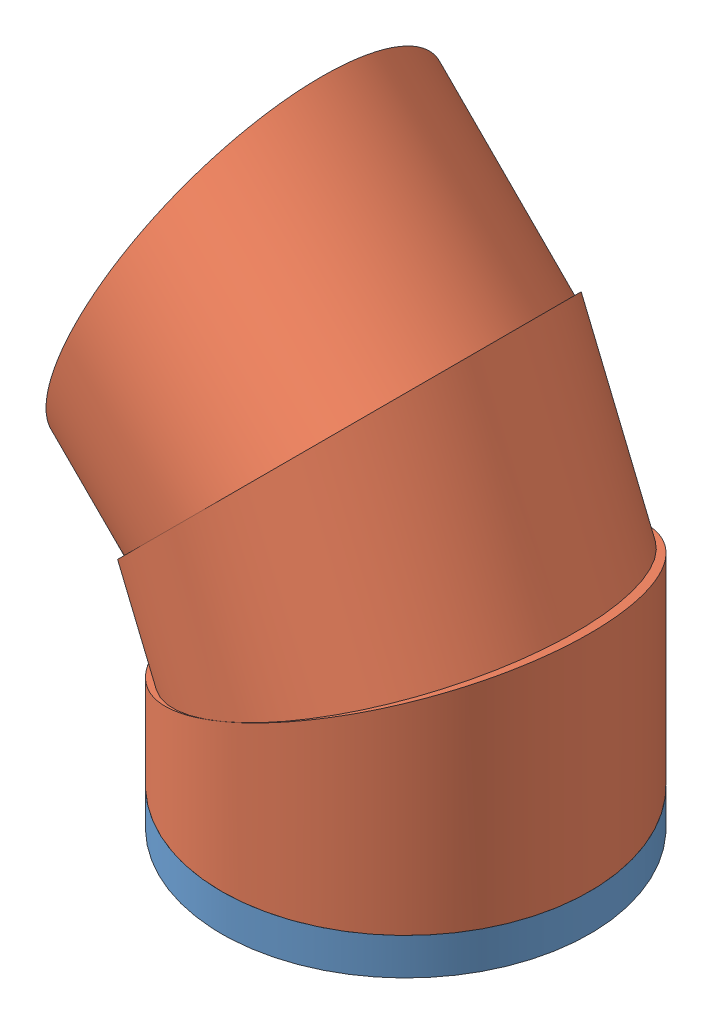
SolidWorks assembly test1, configuration 默认. Lengths in mm.
Overall size (43.08 49.57 30).
4 component instances, 2 part files, 6 mates.
Components (placement in the parent):
- grd-1: grd [默认] at (0.7311 -6.288 30) size (30 3 30)
- p0-1: p0 [默认] at (0.7311 -3.288 30) size (30 18.21 30)
- p0-4: p0 [默认] at (0.7311 8.712 30) x (0.92388 0.382683 0) z (0 0 1) size (30 18.21 30)
- p0-5: p0 [默认] at (-3.8611 19.7985 30) x (0.707107 0.707107 0) z (0 0 1) size (30 18.21 30)
Mates (geometry in assembly coordinates):
- 重合1: coincident anti-aligned: plane of grd-1 through (0.7311 -3.288 30) normal (0 1 0); plane of p0-1 through (0.7311 -3.288 30) normal (0 -1 0)
- 同心1: concentric aligned: cylinder of grd-1 through (0.7311 -3.288 30) axis (0 -1 0) radius 15; cylinder of p0-1 through (0.7311 16.712 30) axis (0 -1 0) radius 15
- 重合2: coincident anti-aligned: plane of p0-1 through (-14.2689 2.4988 13.5) normal (-0.382683 0.92388 0); plane of p0-4 through (0.7311 8.712 30) normal (0.382683 -0.92388 0)
- 同心2: concentric anti-aligned: circle of p0-1; cylinder of p0-4 through (-6.9226 27.1896 30) axis (0.382683 -0.92388 0) radius 15
- 重合3: coincident anti-aligned: plane of p0-4 through (-15.3416 8.318 13.5) normal (-0.707107 0.707107 0); plane of p0-5 through (-3.8611 19.7985 30) normal (0.707107 -0.707107 0)
- 同心3: concentric anti-aligned: circle of p0-4; cylinder of p0-5 through (-18.0032 33.9407 30) axis (0.707107 -0.707107 0) radius 15
